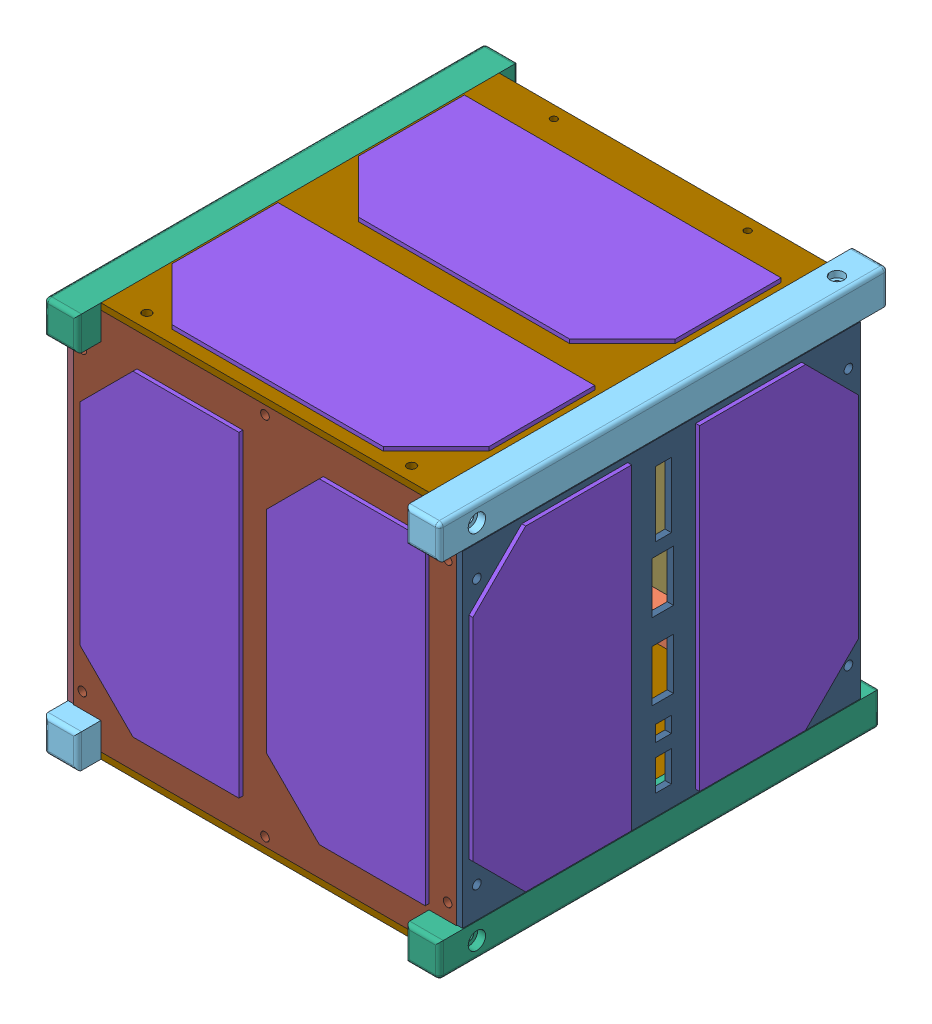
SolidWorks assembly sample, configuration ﾃﾞﾌｫﾙﾄ. Lengths in mm.
Overall size (101 102 113.5).
41 component instances, 13 part files, 21 mates.
Components (placement in the parent):
- B2_main-1: B2_main [ﾃﾞﾌｫﾙﾄ] at origin size (100 100 113.5)
  - B3_flame1-1: B3_flame1 [Default] at origin size (96.8 96.8 4)
  - B3_flame2-1: B3_flame2 [Default] at (76.5 -8.5 -87.5) x (-1 0 0) z (0 1 0) size (83 5 6.9)
  - B3_flame3-1: B3_flame3 [Default] at (100 -8.5 -85.4016) x (-1 0 0) z (0 1 0) size (6.9 5 83)
  - B3_flame4-1: B3_flame4 [Default] at (20.0069 -89.5 -26.6402) x (1 0 0) z (0 -1 0) size (6.9 16 10.5)
  - B3_flame5-1: B3_flame5 [Default] at (100 -8.5 11.5) x (-1 0 0) z (0 1 0) size (23.5 113.5 18.5)
  - B3_flame6-1: B3_flame6 [Default] at (91.5 -91.5 11.5) x (1 0 0) z (0 -1 0) size (23.5 111.5 18.5)
  - B3_flame5-2: B3_flame5 [Default] at (0 -91.5 11.5) x (1 0 0) z (0 -1 0) size (23.5 113.5 18.5)
  - B3_flame6-2: B3_flame6 [Default] at (8.5 -8.5 11.5) x (-1 0 0) z (0 1 0) size (23.5 111.5 18.5)
  - B3_flame2-2: B3_flame2 [Default] at (23.5 -91.5 -87.5) x (1 0 0) z (0 -1 0) size (83 5 6.9)
  - B3_flame3-2: B3_flame3 [Default] at (0 -91.5 -85.4016) x (1 0 0) z (0 -1 0) size (6.9 5 83)
  - B3_flame4-2: B3_flame4 [Default] at (79.9931 -10.5 -26.6402) x (-1 0 0) z (0 1 0) size (6.9 16 10.5)
  - B3_flame4-3: B3_flame4 [Default] at (-9.9069 -10.5 -26.6402) x (-1 0 0) z (0 1 0) size (6.9 16 10.5)
  - B3_flame4-4: B3_flame4 [Default] at (109.9069 -10.5 -61.3598) x (1 0 0) z (0 1 0) size (6.9 16 10.5)
  - B3_flame4-5: B3_flame4 [Default] at (109.9069 -89.5 -26.6402) x (1 0 0) z (0 -1 0) size (6.9 16 10.5)
  - B3_flame4-6: B3_flame4 [Default] at (-9.9069 -89.5 -61.3598) x (-1 0 0) z (0 -1 0) size (6.9 16 10.5)
  - B3_flame4-7: B3_flame4 [Default] at (79.9931 -89.5 -61.3598) x (-1 0 0) z (0 -1 0) size (6.9 16 10.5)
  - B3_flame4-8: B3_flame4 [Default] at (20.0069 -10.5 -61.3598) x (1 0 0) z (0 1 0) size (6.9 16 10.5)
  - B3_flame7-1: B3_flame7 [Default] at (4.25 -91.5 -96.25) x (1 0 0) z (0 -1 0) size (5.5 8.5 5)
  - B3_flame7-2: B3_flame7 [Default] at (95.75 -8.5 -96.25) x (-1 0 0) z (0 1 0) size (5.5 8.5 5)
- B3_±Y_panel-1: B3_±Y_panel [Default] at (-6.4374 35.5175 36.7952) x (-1 0 0) z (0 0 -1) size (83 2.6 100.7)
  - Solar panel-1: Solar panel [Default] at (-43.4703 -35.5175 64.7205) size (80.15 1 40.15)
  - Solar panel-2: Solar panel [Default] at (-69.4046 -34.5175 111.8705) x (-1 0 0) z (0 0 1) size (80.15 1 40.15)
  - B2_±X_panel-2: B2_±X_panel [Default] at (-32.6974 -37.1175 99.3327) x (-1 0 0) z (0 0 -1) size (83 1.6 100.7)
- B3_±Y_panel-2: B3_±Y_panel [Default] at (106.4374 -135.5175 36.7952) x (1 0 0) z (0 0 -1) size (83 2.6 100.7)
  - Solar panel-1: Solar panel [Default] at (-43.4703 -35.5175 64.7205) size (80.15 1 40.15)
  - Solar panel-2: Solar panel [Default] at (-69.4046 -34.5175 111.8705) x (-1 0 0) z (0 0 1) size (80.15 1 40.15)
  - B2_±X_panel-2: B2_±X_panel [Default] at (-32.6974 -37.1175 99.3327) x (-1 0 0) z (0 0 -1) size (83 1.6 100.7)
- B3_+X_panel-1: B3_+X_panel [Default] at (78.7507 -74.7061 -48) x (0 1 0) z (0 0 -1) size (82.6 2.6 100.7)
  - Solar panel-2: Solar panel [Default] at (37.4682 21.2493 -21.6831) size (80.15 1 40.15)
  - Solar panel-3: Solar panel [Default] at (11.5339 21.2493 15.1831) x (-1 0 0) z (0 0 -1) size (80.15 1 40.15)
  - B3_+X_panel-1: B3_+X_panel [Default] at (0.9661 19.6493 -22.1375) size (82.6 1.6 100.7)
- B3_+Z_panel-1: B3_+Z_panel [Default] at (-143.4944 -153.976 4.9) x (-1 0 0) z (0 1 0) size (96.8 2.6 96.8)
  - B2_+Z_panel-1: B2_+Z_panel [Default] at (-207.8501 -0.9 90.2045) size (96.8 1.6 96.8)
  - Solar panel-1: Solar panel [Default] at (-225.2113 0.7 116.9431) x (0 0 1) z (-1 0 0) size (80.15 1 40.15)
  - Solar panel-2: Solar panel [Default] at (-178.0613 1.7 91.0089) x (0 0 -1) z (-1 0 0) size (80.15 1 40.15)
- B3_-Z_panel-1: B3_-Z_panel [ﾃﾞﾌｫﾙﾄ] at (67.2 -63 -89) x (1 0 0) z (0 -1 0) size (96.8 2.6 96.8)
  - B2_-Z_panel-1: B2_-Z_panel [Default] at (-49.4929 -4.5 -25.7556) x (0 0 1) z (1 0 0) size (96.8 1.6 96.8)
  - Solar panel-1: Solar panel [Default] at (15.6169 -6.1 -0.1079) x (0 0 1) z (1 0 0) size (80.15 1 40.15)
  - Solar panel-2: Solar panel [Default] at (-31.5331 -7.1 -26.0421) x (0 0 -1) z (1 0 0) size (80.15 1 40.15)
- B3_-X_panel-1: B3_-X_panel [Default] at (0 -73.74 -25.8625) x (0 1 0) z (0 0 -1) size (82.6 1.6 100.7)
Mates (geometry in assembly coordinates):
- Concentric3: concentric aligned: cylinder of B2_main-1/B3_flame1-1 through (83.5 0 2) axis (0 1 0) radius 0.8; cylinder of B3_±Y_panel-1/B2_±X_panel-2 through (83.5 0 2) axis (0 1 0) radius 1.1
- Concentric4: concentric aligned: cylinder of B2_main-1/B3_flame2-1 through (25.5 0 -92) axis (0 1 0) radius 0.8; cylinder of B3_±Y_panel-1/B2_±X_panel-2 through (25.5 0 -92) axis (0 1 0) radius 0.85
- Coincident2: coincident anti-aligned: plane of B2_main-1/B3_flame2-1 through (8.5 -1.6 -83.5) normal (0 1 0); plane of B3_±Y_panel-1/B2_±X_panel-2 through (26.26 -1.6 -62.5375) normal (0 -1 0)
- Concentric9: concentric aligned: cylinder of B2_main-1/B3_flame1-1 through (16.5 -100 2) axis (0 -1 0) radius 0.8; cylinder of B3_±Y_panel-2/B2_±X_panel-2 through (16.5 -100 2) axis (0 -1 0) radius 1.1
- Concentric10: concentric aligned: cylinder of B2_main-1/B3_flame2-2 through (74.5 -100 -92) axis (0 -1 0) radius 0.8; cylinder of B3_±Y_panel-2/B2_±X_panel-2 through (74.5 -100 -92) axis (0 -1 0) radius 0.85
- Coincident3: coincident anti-aligned: plane of B2_main-1/B3_flame2-2 through (91.5 -98.4 -83.5) normal (0 -1 0); plane of B3_±Y_panel-2/B2_±X_panel-2 through (73.74 -98.4 -62.5375) normal (0 1 0)
- Coincident5: coincident anti-aligned: plane of B2_main-1/B3_flame1-1 through (0 0 4) normal (0 0 1); plane of B3_+Z_panel-1/B2_+Z_panel-1 through (64.3556 -63.7715 4) normal (0 0 -1)
- Coincident7: coincident anti-aligned: plane of B2_main-1/B3_flame2-2 through (8.5 -100 -93.5) normal (0 0 -1); plane of B3_-Z_panel-1/B2_-Z_panel-1 through (17.7071 -37.2444 -93.5) normal (0 0 1)
- Concentric285: concentric aligned: cylinder of B2_main-1/B3_flame1-1 through (3.8 -87.5 4) axis (0 0 1) radius 0.8; cylinder of B3_+Z_panel-1/B2_+Z_panel-1 through (3.8 -87.5 5.6) axis (0 0 1) radius 1.1
- Concentric286: concentric aligned: cylinder of B2_main-1/B3_flame1-1 through (96.2 -12.5 4) axis (0 0 1) radius 0.8; cylinder of B3_+Z_panel-1/B2_+Z_panel-1 through (96.2 -12.5 5.6) axis (0 0 1) radius 1.1
- 一致27: coincident anti-aligned: plane of B2_main-1/B3_flame1-1 through (98.4 -91.5 -6) normal (1 0 0); plane of B3_+X_panel-1/B3_+X_panel-1 through (98.4 -73.74 -25.8625) normal (-1 0 0)
- 同心円11: concentric aligned: cylinder of B2_main-1/B3_flame1-1 through (100 -16.5 2) axis (1 0 0) radius 0.8; cylinder of B3_+X_panel-1/B3_+X_panel-1 through (100 -16.5 2) axis (1 0 0) radius 1.1
- 同心円12: concentric aligned: cylinder of B2_main-1/B3_flame1-1 through (100 -83.5 2) axis (1 0 0) radius 0.8; cylinder of B3_+X_panel-1/B3_+X_panel-1 through (100 -83.5 2) axis (1 0 0) radius 1.1
- 同心円13: concentric aligned: cylinder of B2_main-1/B3_flame3-1 through (100 -17.5 -92) axis (1 0 0) radius 0.8; cylinder of B3_+X_panel-1/B3_+X_panel-1 through (100 -17.5 -92) axis (1 0 0) radius 1.1
- 同心円14: concentric aligned: cylinder of B2_main-1/B3_flame3-1 through (100 -82.5 -92) axis (1 0 0) radius 0.8; cylinder of B3_+X_panel-1/B3_+X_panel-1 through (100 -82.5 -92) axis (1 0 0) radius 1.1
- 一致28: coincident anti-aligned: plane of B2_main-1/B3_flame1-1 through (1.6 -8.5 -6) normal (-1 0 0); plane of B3_-X_panel-1 through (1.6 -73.74 -25.8625) normal (1 0 0)
- 同心円15: concentric anti-aligned: cylinder of B2_main-1/B3_flame1-1 through (0 -16.5 2) axis (-1 0 0) radius 0.8; cylinder of B3_-X_panel-1 through (1.6 -16.5 2) axis (1 0 0) radius 1.1
- 同心円16: concentric anti-aligned: cylinder of B2_main-1/B3_flame1-1 through (0 -83.5 2) axis (-1 0 0) radius 0.8; cylinder of B3_-X_panel-1 through (1.6 -83.5 2) axis (1 0 0) radius 1.1
- 一致96: coincident anti-aligned: plane of B2_main-1/B3_flame3-2 through (8.5 -91.5 -93.5) normal (0 0 -1); plane of B3_-Z_panel-1/B2_-Z_panel-1 through (17.7071 -37.2444 -93.5) normal (0 0 1)
- 同心円56: concentric aligned: cylinder of B2_main-1/B3_flame2-1 through (50 -4.5 -93.5) axis (0 0 -1) radius 0.8; cylinder of B3_-Z_panel-1/B2_-Z_panel-1 through (50 -4.5 -95.1) axis (0 0 -1) radius 1.1
- 同心円57: concentric aligned: cylinder of B2_main-1/B3_flame2-2 through (50 -95.5 -93.5) axis (0 0 -1) radius 0.8; cylinder of B3_-Z_panel-1/B2_-Z_panel-1 through (50 -95.5 -95.1) axis (0 0 -1) radius 1.1
